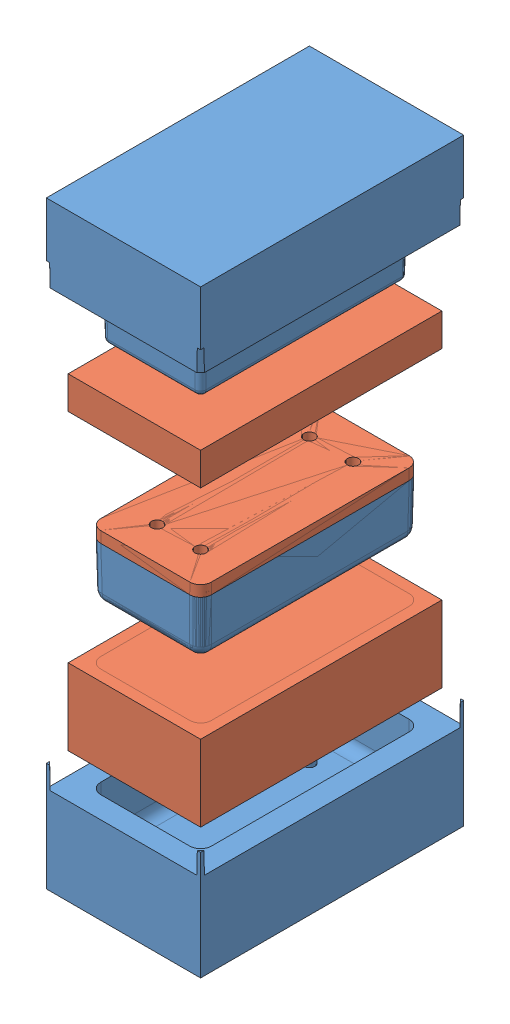
SolidWorks assembly Assem1, configuration Default. Lengths in mm.
Overall size (141.75 550 241.75).
2 component instances, 2 part files, 3 mates.
Components (placement in the parent):
- done-1: done [Default] at (89.1907 65.316 157.6978) x (-1 0 0) z (0 -1 0) size (141.75 241.75 550)
- donelid-2: donelid [Default] at (354.6972 115.316 -252.1381) size (121.75 300 221.75)
Mates (geometry in assembly coordinates):
- Coincident4: coincident anti-aligned: plane of done-1 through (89.1907 115.316 157.6978) normal (0 1 0); plane of donelid-2 through (130.062 115.316 248.569) normal (0 -1 0)
- Coincident6: coincident anti-aligned: line of done-1 through (130.065 115.316 258.5705) axis (-1 0 0); line of donelid-2 through (48.3165 115.316 258.5705) axis (1 0 0)
- Coincident7: coincident anti-aligned: line of done-1 through (38.318 115.316 248.5721) axis (0 0 -1); line of donelid-2 through (38.318 115.316 66.8235) axis (0 0 1)
